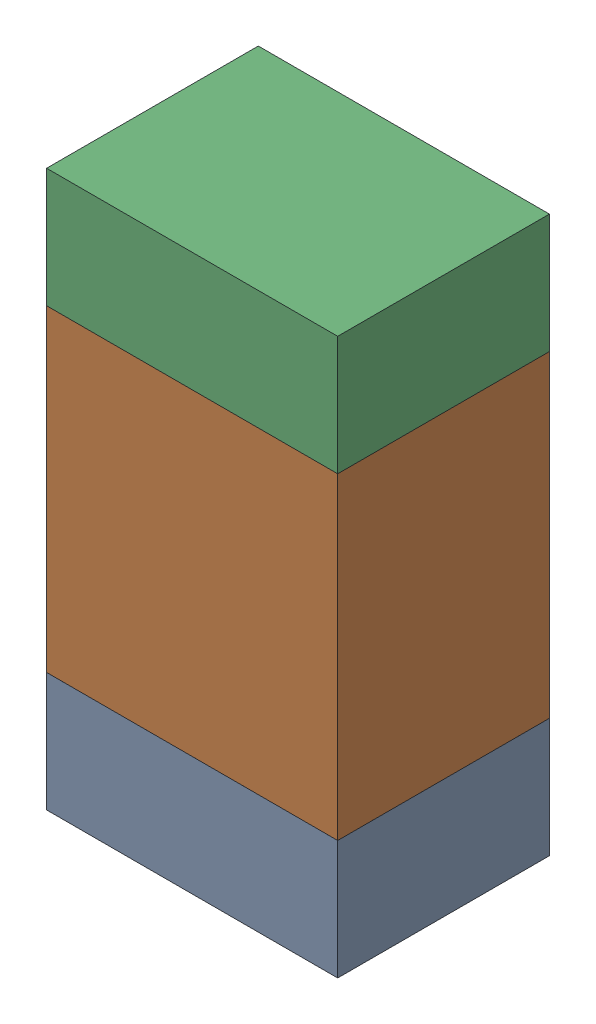
SolidWorks assembly R406PCB, configuration Default. Lengths in mm.
Overall size (0.55 1.05 0.4).
6 component instances, 2 part files, 0 mates.
Components (placement in the parent):
- 846483288-1: 846483288 [Default] at (84.5901 90.0874 0) size (0.55 0.22 0.4)
  - Extruded_12-1: Extruded_12 [Default] at origin size (0.55 0.22 0.4)
- 846483424-1: 846483424 [Default] at (84.5901 90.4999 0) size (0.55 0.6 0.4)
  - Extruded_13-1: Extruded_13 [Default] at origin size (0.55 0.6 0.4)
- 846483288-2: 846483288 [Default] at (84.5901 90.9124 0) size (0.55 0.22 0.4)
  - Extruded_12-1: Extruded_12 [Default] at origin size (0.55 0.22 0.4)
